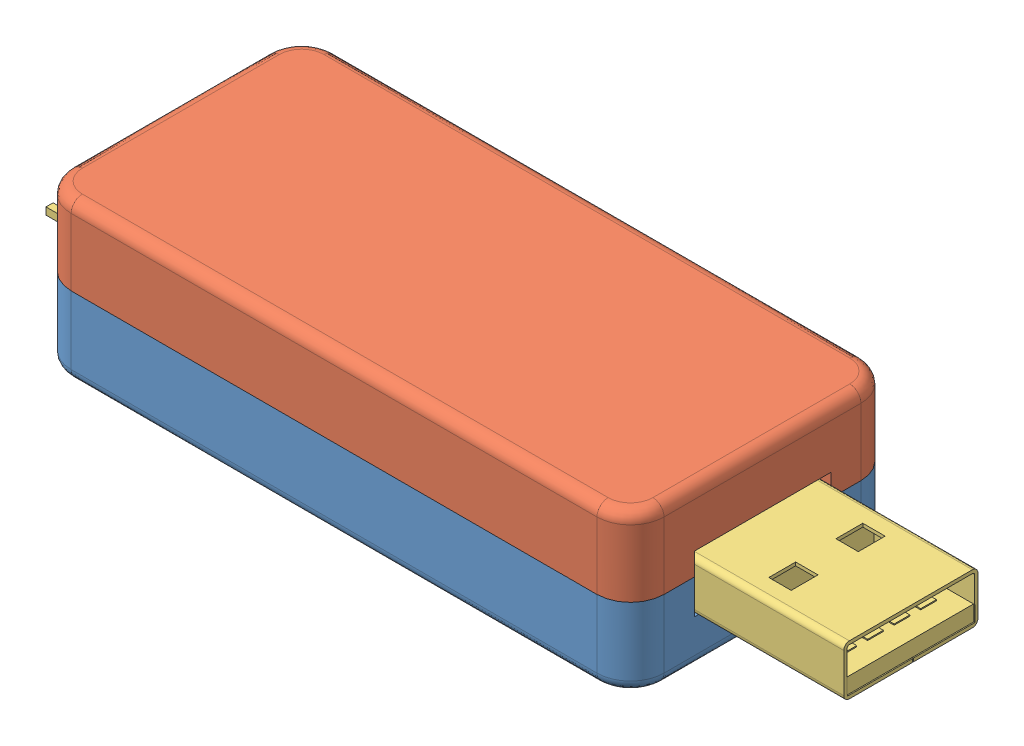
SolidWorks assembly Assembly, configuration Default. Lengths in mm.
Overall size (72.94 14.22 23.6).
3 component instances, 3 part files, 4 mates.
Components (placement in the parent):
- Bottom-1: Bottom [Default] at (-39.1381 25.2598 46.3587) size (53 7.1 23.6)
- Top-1: Top [Default] at (-39.1381 39.3476 22.7587) x (1 0 0) z (0 0 -1) size (53 9.6 23.6)
- PCB.step-2: PCB.step [Default] at (11.8869 29.7574 24.8087) x (-1 0 0) z (0 1 0) size (72.94 19.5 12.58)
Mates (geometry in assembly coordinates):
- Parallel1: parallel: plane of assembly; plane of Bottom-1 through (-39.1381 25.2598 34.5587) normal (0 0 1); plane of assembly
- Distance1: distance = 0 mm anti-aligned: plane of Bottom-1 through (-12.6381 25.2598 46.3587) normal (1 0 0)
- Parallel3: parallel: plane of Bottom-1 through (-39.1381 25.2598 34.5587) normal (0 0 1); plane of Top-1 through (-39.1381 39.3476 34.5587) normal (0 0 -1)
- Distance2: distance = 0 mm aligned: plane of Bottom-1 through (-12.6381 25.2598 46.3587) normal (1 0 0); plane of Top-1 through (-12.6381 39.3476 22.7587) normal (1 0 0)
